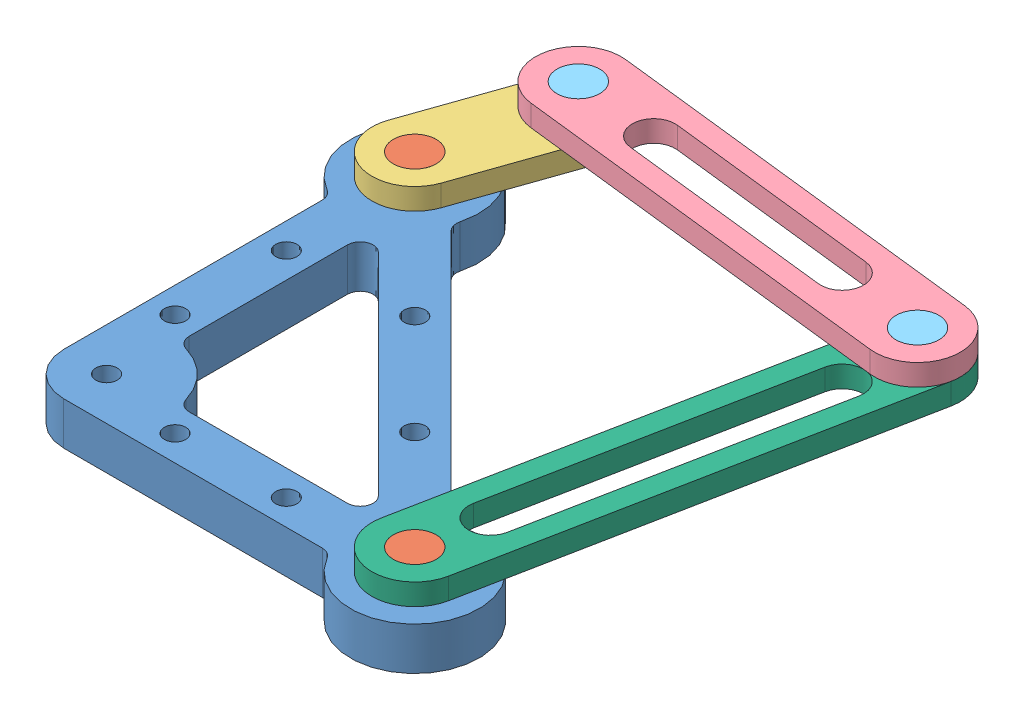
SolidWorks assembly Assembly, configuration Default. Lengths in mm.
Overall size (126.06 20 136.06).
8 component instances, 6 part files, 20 mates.
Components (placement in the parent):
- Plate, Web-1: Plate, Web [Default] at (3.0711 0 -83.0711) size (110 10 110)
- 10x15 PEG-1: 10x15 PEG [Default] at (3.0711 15 -83.0711) x (0 -1 0) z (0.94404 0 0.329832) size (15 10 10)
- Drivelink-1: Drivelink [Default] at (3.0711 10 -83.0711) x (0.329832 0 -0.94404) z (0.94404 0 0.329832) size (50 5 20)
- Centerlink-1: Centerlink [Default] at (12.966 15 -111.3923) x (0.11338 0 -0.993552) z (0.993552 0 0.11338) size (20 5 110)
- 10x10 PEG-1: 10x10 PEG [Default] at (12.966 20 -111.3923) x (0 -1 0) z (-0.970479 0 0.241185) size (10 10 10)
- Rockerlink-1: Rockerlink [Default] at (102.3857 10 -101.1881) x (0.98117 0 0.193146) z (-0.193146 0 0.98117) size (20 5 120)
- 10x15 PEG-2: 10x15 PEG [Default] at (83.0711 15 -3.0711) x (0 -1 0) z (-0.751523 0 0.659707) size (15 10 10)
- 10x10 PEG-2: 10x10 PEG [Default] at (102.3857 20 -101.1881) x (0 -1 0) z (-0.679622 0 0.733562) size (10 10 10)
Mates (geometry in assembly coordinates):
- Coincident1: coincident anti-aligned: plane of Plate, Web-1 through (3.0711 0 -83.0711) normal (0 -1 0)
- Coincident2: coincident: point of Plate, Web-1
- Concentric1: concentric anti-aligned: cylinder of Plate, Web-1 through (3.0711 10 -83.0711) axis (0 -1 0) radius 5; cylinder of 10x15 PEG-1 through (3.0711 0 -83.0711) axis (0 1 0) radius 5
- Coincident3: coincident aligned: plane of Plate, Web-1 through (3.0711 0 -83.0711) normal (0 -1 0); plane of 10x15 PEG-1 through (3.0711 0 -83.0711) normal (0 -1 0)
- Concentric2: concentric anti-aligned: cylinder of 10x15 PEG-1 through (3.0711 0 -83.0711) axis (0 1 0) radius 5; cylinder of Drivelink-1 through (3.0711 15 -83.0711) axis (0 -1 0) radius 5
- Coincident4: coincident aligned: plane of 10x15 PEG-1 through (3.0711 15 -83.0711) normal (0 1 0); plane of Drivelink-1 through (3.0711 15 -83.0711) normal (0 1 0)
- Concentric3: concentric anti-aligned: cylinder of Drivelink-1 through (12.966 15 -111.3923) axis (0 -1 0) radius 5; cylinder of 10x10 PEG-1 through (12.966 10 -111.3923) axis (0 1 0) radius 5
- Coincident5: coincident aligned: plane of Drivelink-1 through (3.0711 10 -83.0711) normal (0 -1 0); plane of 10x10 PEG-1 through (12.966 10 -111.3923) normal (0 -1 0)
- Concentric4: concentric anti-aligned: cylinder of Centerlink-1 through (12.966 20 -111.3923) axis (0 -1 0) radius 5; cylinder of 10x10 PEG-1 through (12.966 10 -111.3923) axis (0 1 0) radius 5
- Coincident6: coincident aligned: plane of Centerlink-1 through (12.966 20 -111.3923) normal (0 1 0); plane of 10x10 PEG-1 through (12.966 20 -111.3923) normal (0 1 0)
- Coincident7: coincident anti-aligned: plane of Plate, Web-1 through (3.0711 10 -83.0711) normal (0 1 0); plane of Rockerlink-1 through (102.3857 10 -101.1881) normal (0 -1 0)
- Concentric5: concentric anti-aligned: cylinder of Plate, Web-1 through (83.0711 10 -3.0711) axis (0 -1 0) radius 5; cylinder of 10x15 PEG-2 through (83.0711 0 -3.0711) axis (0 1 0) radius 5
- Coincident8: coincident aligned: plane of Plate, Web-1 through (3.0711 0 -83.0711) normal (0 -1 0); plane of 10x15 PEG-2 through (83.0711 0 -3.0711) normal (0 -1 0)
- Concentric6: concentric anti-aligned: cylinder of Rockerlink-1 through (83.0711 15 -3.0711) axis (0 -1 0) radius 5; cylinder of 10x15 PEG-2 through (83.0711 0 -3.0711) axis (0 1 0) radius 5
- Coincident9: coincident aligned: plane of Rockerlink-1 through (102.3857 15 -101.1881) normal (0 1 0); plane of 10x15 PEG-2 through (83.0711 15 -3.0711) normal (0 1 0)
- Concentric7: concentric anti-aligned: cylinder of Rockerlink-1 through (102.3857 15 -101.1881) axis (0 -1 0) radius 5; cylinder of 10x10 PEG-2 through (102.3857 10 -101.1881) axis (0 1 0) radius 5
- Coincident10: coincident aligned: plane of Rockerlink-1 through (102.3857 10 -101.1881) normal (0 -1 0); plane of 10x10 PEG-2 through (102.3857 10 -101.1881) normal (0 -1 0)
- Concentric8: concentric anti-aligned: cylinder of Centerlink-1 through (102.3857 20 -101.1881) axis (0 -1 0) radius 5; cylinder of 10x10 PEG-2 through (102.3857 10 -101.1881) axis (0 1 0) radius 5
- Coincident11: coincident aligned: plane of Centerlink-1 through (12.966 20 -111.3923) normal (0 1 0); plane of 10x10 PEG-2 through (102.3857 20 -101.1881) normal (0 1 0)
- Coincident13: coincident aligned: plane of 10x15 PEG-1 through (3.0711 15 -83.0711) normal (0.329832 0 -0.94404); plane of Drivelink-1 through (3.0711 10 -83.0711) normal (0.329832 0 -0.94404)
